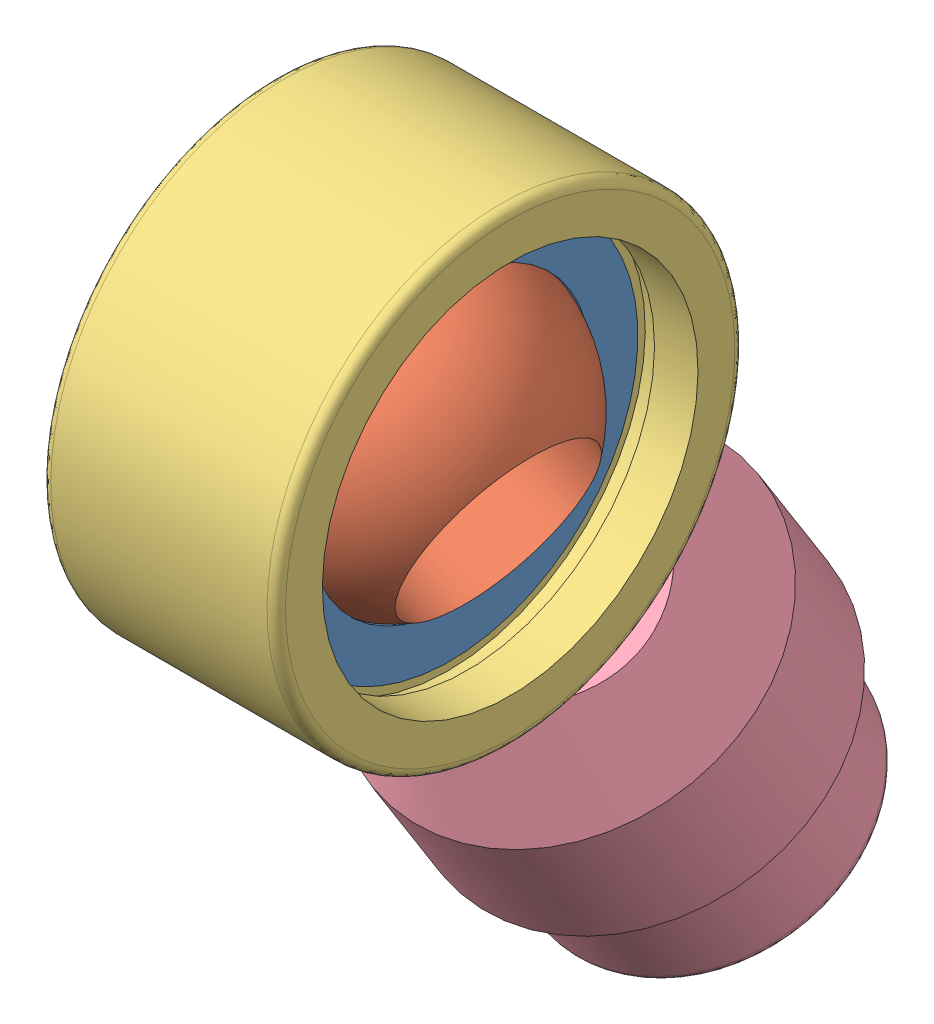
SolidWorks assembly Control_Arm_Bearing, configuration Default. Lengths in mm.
Overall size (21.01 45.11 37.84).
4 component instances, 4 part files, 4 mates.
Components (placement in the parent):
- Ring-1: Ring [Default] at (0.8827 9.1513 20.121) size (6.1 20.32 20.32)
- Bearing-2: Bearing [Default] at (0.8827 9.1513 20.121) x (0.911632 -0.410499 0.020425) z (0.278256 0.652998 0.704391) size (12.69 16.26 16.26)
- Housing-1: Housing [Default] at (0.8347 9.1513 20.121) x (0 -0.999963 0.008566) z (0 0.008566 0.999963) size (25.3 12.7 25.3)
- Control_head-2: Control_head [Default] at (0.8112 6.1129 18.2814) x (0 -0.845979 -0.533217) z (-0.026616 -0.533028 0.845679) size (20.97 19 19)
Mates (geometry in assembly coordinates):
- Tangent2: tangent aligned: sphere of Ring-1; sphere of Bearing-2
- Coincident1: coincident anti-aligned: plane of Ring-1 through (-2.1653 9.1513 20.121) normal (-1 0 0); plane of Housing-1 through (-2.1653 9.1513 20.121) normal (1 0 0)
- Concentric4: concentric aligned: circle of Ring-1; circle of Housing-1
- Perpendicular4: perpendicular: cylinder of Housing-1 through (7.1847 9.1513 20.121) axis (-1 0 0) radius 12.65; cylinder of Control_head-2 through (0.8112 6.1129 18.2814) axis (0 0.845979 0.533217) radius 9.5
